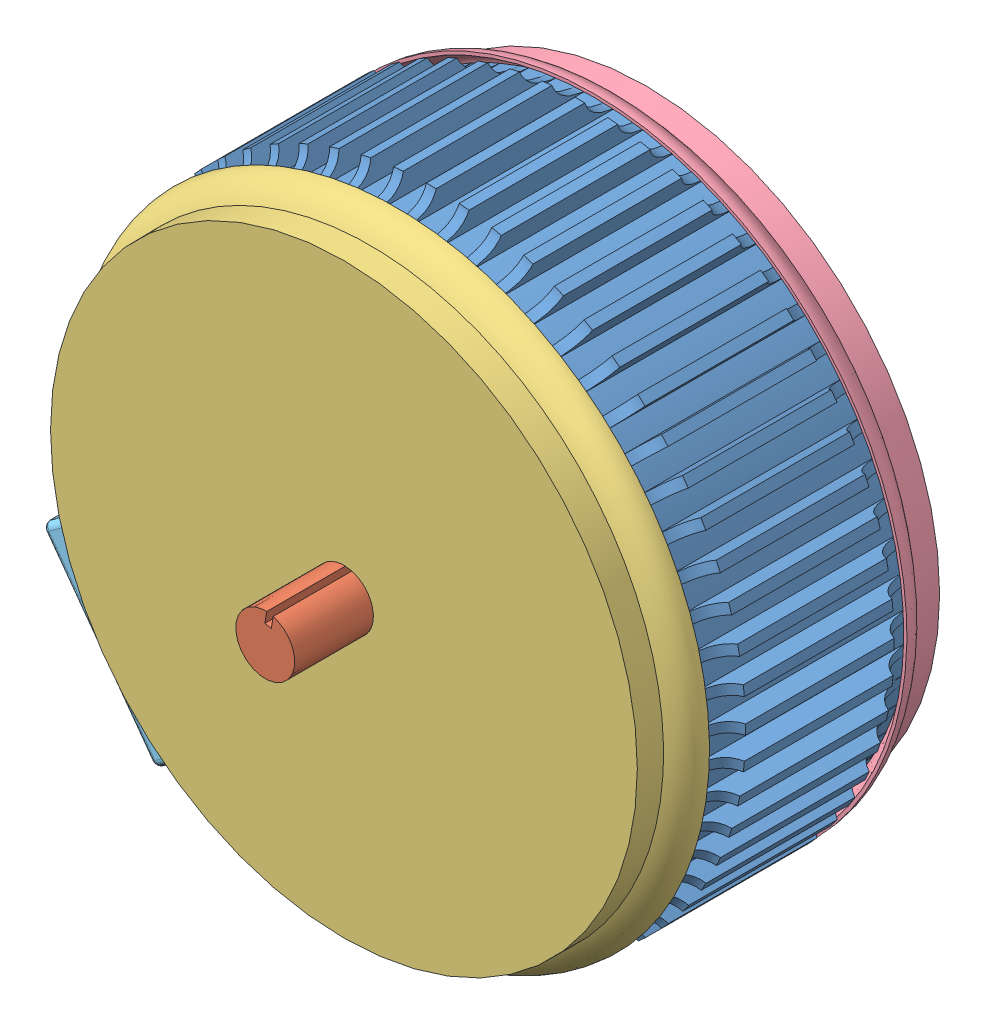
SolidWorks assembly motor electrico completo, configuration Default. Lengths in mm.
Overall size (102.61 95.88 58.11).
5 component instances, 5 part files, 9 mates.
Components (placement in the parent):
- electric motor extruded-1: electric motor extruded [Default] at (23.0602 28.6859 65.7164) x (1 0.000914 0) z (0 0 1) size (95.79 95.79 33.51)
- rotor-1: rotor [Default] at (23.0602 28.6859 69.1164) x (0.987201 -0.15948 0) z (0 0 1) size (53.8 53.73 50)
- tapamotorelectrico hueco-2: tapamotorelectrico hueco [Default] at (23.0602 28.6859 107.1164) x (1 0 0) z (0 0 -1) size (95.5 95.5 8)
- tapamotorelectrico-2: tapamotorelectrico [Default] at (23.0602 28.6859 61.0095) size (95.5 95.5 8)
- trifasaico-1: trifasaico [Default] at (-11.0613 -21.112 169.8654) x (0 0 -1) z (0.808479 0.588524 0) size (27.79 29.47 14.01)
Mates (geometry in assembly coordinates):
- Concentric2: concentric anti-aligned: circle of electric motor extruded-1; circle of rotor-1
- Coincident2: coincident aligned: plane of electric motor extruded-1 through (23.0602 28.6859 99.1164) normal (0 0 1); plane of rotor-1 through (23.0602 28.6859 99.1164) normal (0 0 1)
- Concentric3: concentric anti-aligned: cylinder of rotor-1 through (23.0602 28.6859 119.1164) axis (0 0 -1) radius 4.5; cylinder of tapamotorelectrico hueco-2 through (23.0602 28.6859 97.1164) axis (0 0 1) radius 4.5
- Coincident3: coincident anti-aligned: plane of electric motor extruded-1 through (23.0602 28.6859 99.1164) normal (0 0 1); plane of tapamotorelectrico hueco-2 through (23.0602 28.6859 99.1164) normal (0 0 -1)
- Concentric4: concentric anti-aligned: circle of electric motor extruded-1; circle of tapamotorelectrico-2
- Tangent3: tangent: circle of electric motor extruded-1; face of tapamotorelectrico-2
- Coincident4: coincident anti-aligned: plane of electric motor extruded-1 through (-5.9567 -4.3361 0) normal (-0.808479 -0.588524 0); plane of trifasaico-1 through (-3.2805 -8.0125 71.6939) normal (0.808479 0.588524 0)
- Coincident5: coincident anti-aligned: line of electric motor extruded-1 through (-20.2849 15.3472 71.0405) axis (0.588524 -0.808479 0); line of trifasaico-1 through (-3.543 -7.6519 71.0405) axis (-0.588524 0.808479 0)
- Coincident6: coincident aligned: line of electric motor extruded-1 through (-20.2849 15.3472 71.0405) axis (0 0 1); line of trifasaico-1 through (-20.2849 15.3472 72.2549) axis (0 0 1)
